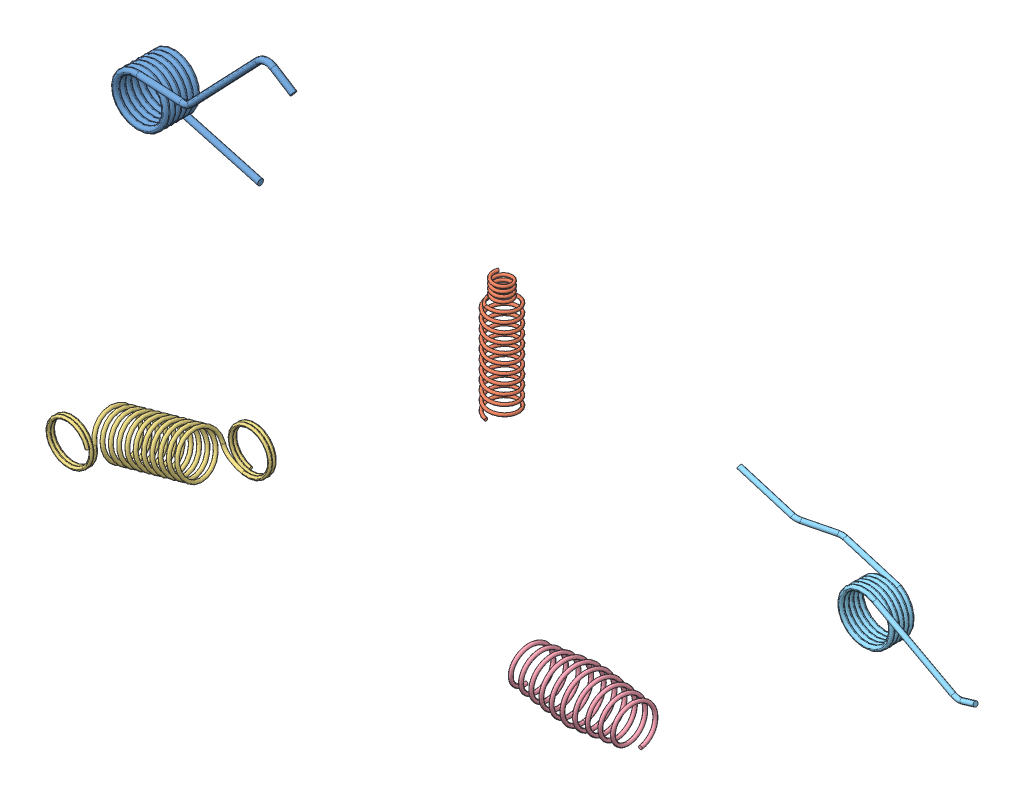
SolidWorks assembly Assemblage position fermée, configuration Défaut. Lengths in mm.
Overall size (152.19 76.46 16.27).
5 component instances, 5 part files, 0 mates.
Components (placement in the parent):
- ressort 5 position fermée-1: ressort 5 position fermée [Défaut] at (-67.7957 14.7506 0) x (-0.057735 -0.998332 0) z (0 0 1) size (26.12 30.87 7.5)
- ressort2-1: ressort2 [Défaut] at (-9.7957 13.1403 3) x (-0.076442 0 0.997074) z (0 -1 0) size (6 6.93 20.19)
- ressort3 position fermée-1: ressort3 position fermée [Défaut] at (-57.7098 -32.3206 5.7) x (0 0 -1) z (-0.963241 -0.268638 0) size (9.7 9.47 31.39)
- ressort6 position fermée-1: ressort6 position fermée [Défaut] at (15.5462 -35.8211 5.0007) x (0.011398 -0.999935 0) z (-0.999935 -0.011398 0) size (8.58 8.62 23.12)
- ressort4 position fermée-1: ressort4 position fermée [Défaut] at (52.2043 -2.2494 -0.1) x (0.473826 0.880619 0) z (0 0 1) size (11.11 42.84 16.27)
